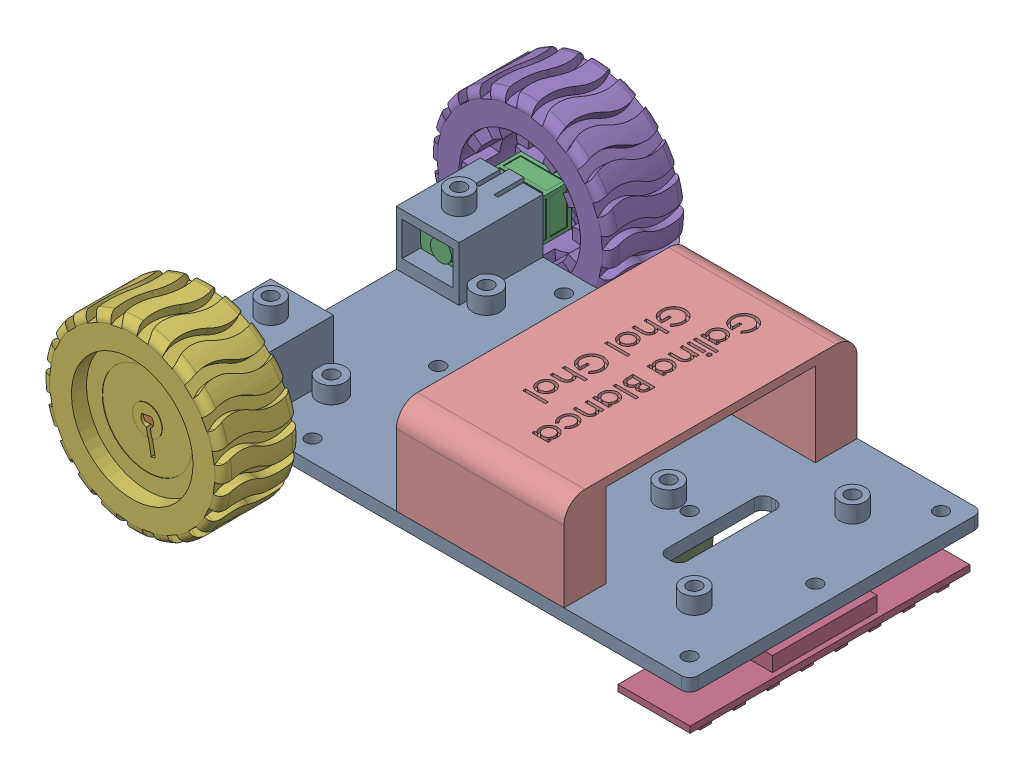
SolidWorks assembly LineFollowerAsy, configuration Default. Lengths in mm.
Overall size (142.52 59.93 111.26).
10 component instances, 7 part files, 22 mates.
Components (placement in the parent):
- Chasis-1: Chasis [Default] at (-35.0248 -8.4054 20.456) size (120 20 72.4)
- MotorModel-1: MotorModel [Default] at (-87.5748 0.5446 63.756) x (-1 0 0) z (0 -1 0) size (12 33.1 10)
- MotorModel-2: MotorModel [Default] at (-87.5748 0.5446 -22.844) x (-1 0 0) z (0 1 0) size (12 33.1 10)
- IRSensorModel-1: IRSensorModel [Default] at (6.2252 -16.4054 53.831) x (0 0 -1) z (0 -1 0) size (66.75 17.25 6.75)
- wheelModel-1: wheelModel [Default] at (-87.5748 0.5446 -16.544) x (0.504264 0.86355 0) z (-0.86355 0.504264 0) size (43.82 18.76 43.82)
- wheelModel-2: wheelModel [Default] at (-87.5748 0.5446 57.456) x (0.983004 0.183585 0) z (0.183585 -0.983004 0) size (43.82 18.76 43.82)
- IRSensorSpacer-1: IRSensorSpacer [Default] at (9.9752 -16.4054 39.331) x (0.998855 0 -0.047831) z (0.047831 0 0.998855) size (8 8 8)
- IRSensorSpacer-2: IRSensorSpacer [Default] at (9.9752 -16.4054 1.581) x (0.619794 0 -0.784765) z (0.784765 0 0.619794) size (8 8 8)
- FreeWheeler-1: FreeWheeler [Default] at (-15.0248 -8.4054 20.456) x (-0.837169 0 -0.546944) z (-0.546944 0 0.837169) size (15 12.6 15)
- cover-1: cover [Default] at (-25.0248 14.5946 20.456) x (0 0 1) z (-1 0 0) size (70 22 40)
Mates (geometry in assembly coordinates):
- Distance3: distance = 0.05 mm anti-aligned: plane of MotorModel-1 through (-93.5748 5.5446 54.756) normal (-1 0 0); plane of Chasis-1 through (-93.6248 5.5946 55.456) normal (1 0 0)
- Distance6: distance = 0.05 mm anti-aligned: plane of Chasis-1 through (-81.5248 -4.5054 55.456) normal (0 1 0); plane of MotorModel-2 through (-81.5748 -4.4554 -13.844) normal (0 -1 0)
- Distance7: distance = 0.05 mm anti-aligned: plane of MotorModel-1 through (-81.5748 -4.4554 54.756) normal (0 -1 0); plane of Chasis-1 through (-81.5248 -4.5054 55.456) normal (0 1 0)
- Concentric6: concentric anti-aligned: cylinder of MotorModel-2 through (-87.5748 0.5446 -30.844) axis (0 0 1) radius 1.5; cylinder of wheelModel-1 through (-87.5748 0.5446 -23.644) axis (0 0 -1) radius 4
- Distance9: distance = 0.8 mm anti-aligned: plane of wheelModel-1 through (-87.5748 0.5446 -23.644) normal (0 0 1); plane of MotorModel-2 through (-87.5748 0.5446 -22.844) normal (0 0 -1)
- Distance10: distance = 0.05 mm anti-aligned: plane of MotorModel-2 through (-81.5748 -4.4554 -13.844) normal (1 0 0); plane of Chasis-1 through (-81.5248 5.5946 55.456) normal (-1 0 0)
- Distance11: distance = 2 mm anti-aligned: plane of wheelModel-1 through (-87.5748 0.5446 -16.544) normal (0 0 1); plane of Chasis-1 through (-95.0248 -5.4054 -14.544) normal (0 0 -1)
- Coincident18: coincident anti-aligned: plane of Chasis-1 through (-95.0248 -2.5054 39.756) normal (0 0 1); plane of MotorModel-1 through (-85.0748 -0.9554 39.756) normal (0 0 -1)
- Concentric7: concentric anti-aligned: cylinder of MotorModel-1 through (-87.5748 0.5446 71.756) axis (0 0 -1) radius 1.5; cylinder of wheelModel-2 through (-87.5748 0.5446 72.356) axis (0 0 1) radius 14.5
- Distance12: distance = 0.8 mm anti-aligned: plane of MotorModel-1 through (-87.5748 0.5446 63.756) normal (0 0 1); plane of wheelModel-2 through (-87.5748 0.5446 64.556) normal (0 0 -1)
- Concentric8: concentric aligned: cylinder of Chasis-1 through (9.9752 7.5956 39.331) axis (0 -1 0) radius 1.625; cylinder of IRSensorSpacer-1 through (9.9752 -8.4054 39.331) axis (0 -1 0) radius 4
- Concentric9: concentric aligned: cylinder of IRSensorModel-1 through (9.9752 -16.4054 39.331) axis (0 -1 0) radius 1.6; cylinder of IRSensorSpacer-1 through (9.9752 -8.4054 39.331) axis (0 -1 0) radius 4
- Coincident21: coincident anti-aligned: plane of IRSensorModel-1 through (6.2252 -16.4054 53.831) normal (0 1 0); plane of IRSensorSpacer-1 through (9.9752 -16.4054 39.331) normal (0 -1 0)
- Coincident22: coincident anti-aligned: plane of Chasis-1 through (-35.0248 -8.4054 20.456) normal (0 -1 0); plane of IRSensorSpacer-1 through (9.9752 -8.4054 39.331) normal (0 1 0)
- Concentric10: concentric aligned: cylinder of Chasis-1 through (9.9752 7.5956 1.581) axis (0 -1 0) radius 1.625; cylinder of IRSensorSpacer-2 through (9.9752 -8.4054 1.581) axis (0 -1 0) radius 4
- Concentric11: concentric aligned: cylinder of IRSensorModel-1 through (9.9752 -16.4054 1.581) axis (0 -1 0) radius 1.6; cylinder of IRSensorSpacer-2 through (9.9752 -8.4054 1.581) axis (0 -1 0) radius 4
- Coincident23: coincident anti-aligned: plane of IRSensorModel-1 through (6.2252 -16.4054 53.831) normal (0 1 0); plane of IRSensorSpacer-2 through (9.9752 -16.4054 1.581) normal (0 -1 0)
- Concentric12: concentric anti-aligned: cylinder of Chasis-1 through (-15.0248 7.5956 20.456) axis (0 -1 0) radius 1.625; cylinder of FreeWheeler-1 through (-15.0248 -20.4054 20.456) axis (0 1 0) radius 1.625
- Coincident24: coincident anti-aligned: plane of Chasis-1 through (-35.0248 -8.4054 20.456) normal (0 -1 0); plane of FreeWheeler-1 through (-15.0248 -8.4054 20.456) normal (0 1 0)
- Concentric13: concentric: cylinder of Chasis-1 through (-10.0248 -8.4054 50.456) axis (0 1 0) radius 1.625; cylinder of cover-1 through (-10.0248 -5.4054 50.456) axis (0 1 0) radius 1.75
- Concentric14: concentric: circle of Chasis-1; cylinder of cover-1 through (-40.0248 -5.4054 -9.544) axis (0 1 0) radius 1.75
- Coincident25: coincident anti-aligned: plane of Chasis-1 through (-35.0248 -5.4054 20.456) normal (0 1 0); plane of cover-1 through (-25.0248 -5.4054 20.456) normal (0 -1 0)
